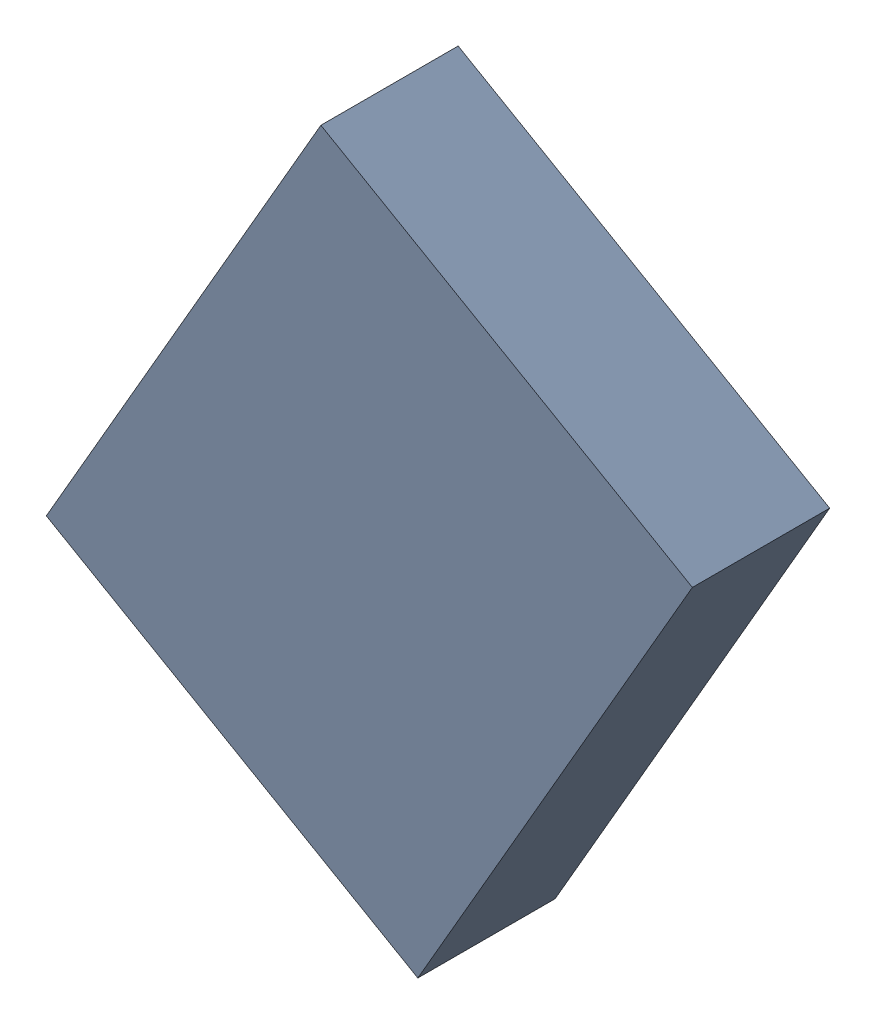
SolidWorks assembly X_TDA_TDA3, configuration Standard. Lengths in mm.
Overall size (3.77 4.02 0.8).
2 component instances, 1 part files, 0 mates.
Components (placement in the parent):
- 885545368-1: 885545368 [Standard] at (35.1741 -22.7679 0) size (3.77 4.02 0.8)
  - Extruded-1: Extruded [Standard] at origin size (3.77 4.02 0.8)
